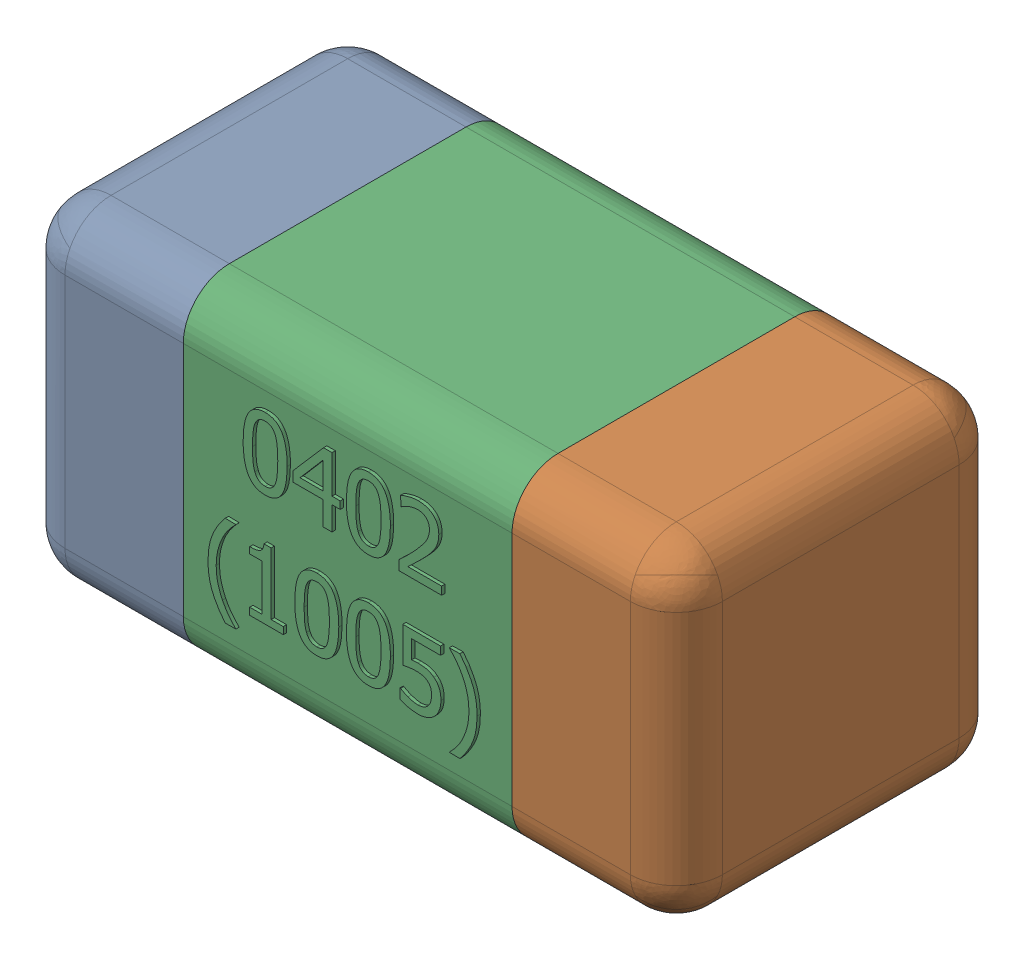
SolidWorks assembly C27, configuration Standard. Lengths in mm.
Overall size (1.01 0.51 0.51).
4 component instances, 3 part files, 0 mates.
Components (placement in the parent):
- C27-subassembly-1-1: C27-subassembly-1 [Standard] at (-10.8999 -16.8 0) x (1 0 0) z (0 0 1) size (1.01 0.51 0.51)
  - User Library-0402_Cap-1: User Library-0402_Cap [Standard] at origin size (0.26 0.51 0.51)
  - User Library-0402_Cap-1-1: User Library-0402_Cap-1 [Standard] at origin size (0.26 0.5 0.51)
  - User Library-0402_Cap-2-1: User Library-0402_Cap-2 [Standard] at origin size (0.5 0.5 0.51)
